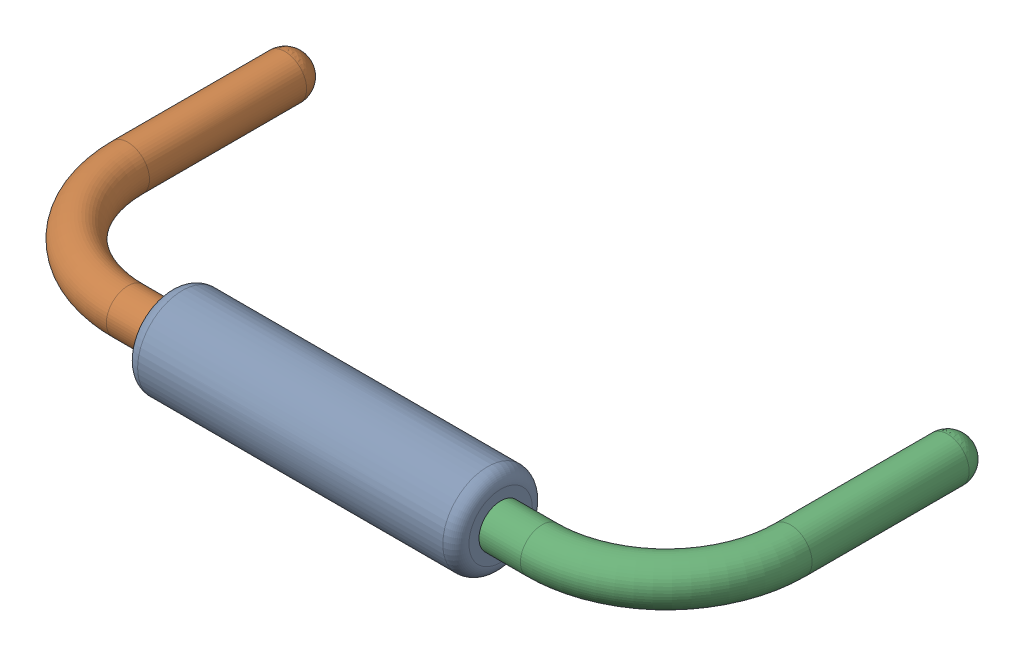
SolidWorks assembly R11, configuration Défaut. Lengths in mm.
Overall size (10.82 1.37 5.33).
4 component instances, 3 part files, 0 mates.
Components (placement in the parent):
- Open CASCADE STEP translator 6.8 1.10.1-1: Open CASCADE STEP translator 6.8 1.10.1 [Défaut] at origin size (10.82 1.37 5.33)
  - Body_1_7-1: Body_1_7 [Défaut] at origin size (5.08 1.37 1.37)
  - Pin_1_4-1: Pin_1_4 [Défaut] at origin size (3.2 0.66 4.98)
  - Pin_2_4-1: Pin_2_4 [Défaut] at (20.32 0 0) x (-1 0 0) z (0 0 1) size (3.2 0.66 4.98)
